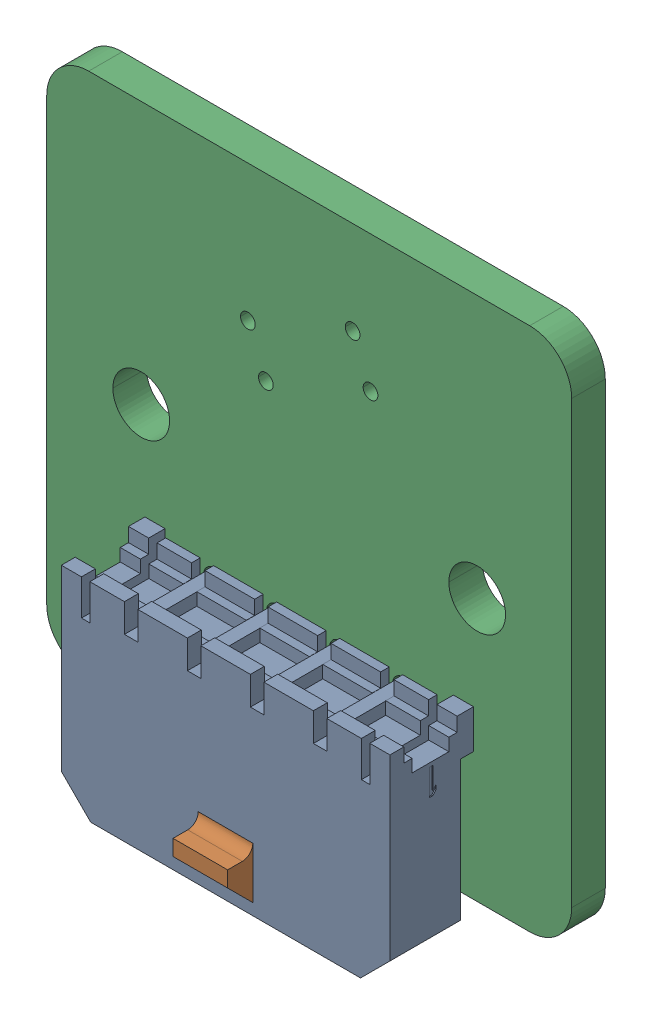
SolidWorks assembly IR Sensor Board.step.STEP, configuration Default. Lengths in mm.
Overall size (25 26.95 8.91).
3 component instances, 2 part files, 0 mates.
Components (placement in the parent):
- 43650-0400.step.STEP-1: 43650-0400.step.STEP [Default] at (32.5 -42 3.65) x (1 0 0) z (0 -1 0) size (15.65 8.91 9.9)
  - COMPOUND.step.STEP-1: COMPOUND.step.STEP [Default] at origin size (15.65 8.91 9.9)
- IR Sensor Board PCB.step.STEP-1: IR Sensor Board PCB.step.STEP [Default] at origin size (25 25 1.6)
